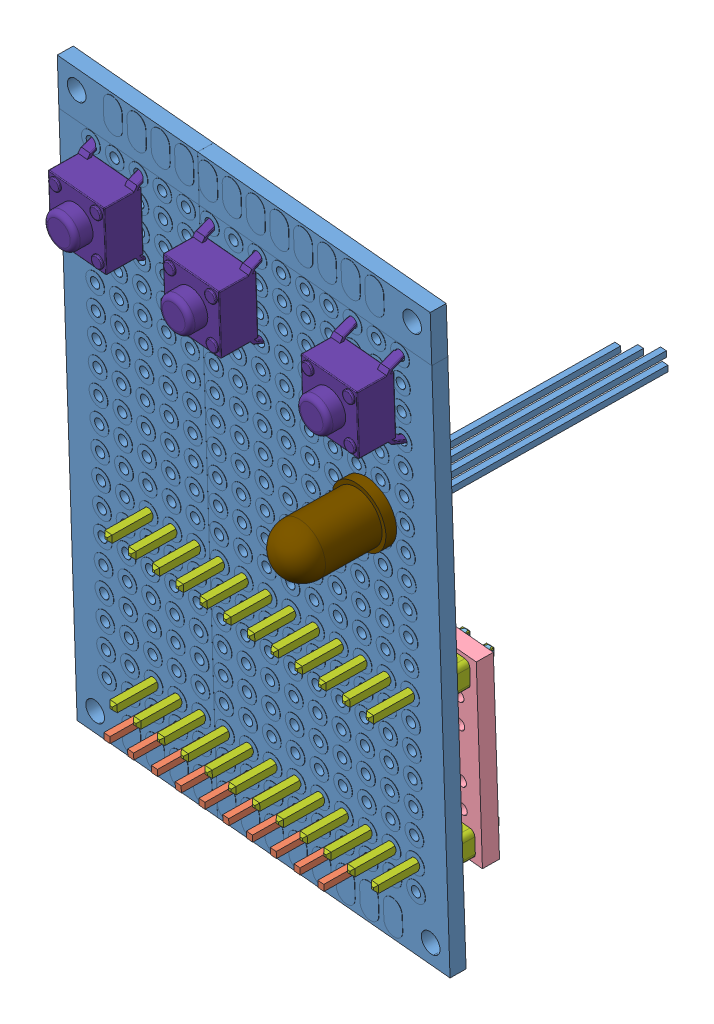
SolidWorks assembly Board avec pièce, configuration Défaut. Lengths in mm.
Overall size (41.2 60.87 36.28).
30 component instances, 20 part files, 9 mates.
Components (placement in the parent):
- board 6x4-2: board 6x4 [Défaut] at (-21.2391 31.2472 3.4753) x (-0.022456 -0.998207 -0.055493) z (-0.066606 -0.05389 0.996323) size (59.85 39.85 1.55)
- User Library-ARDUINO_MINI_V1-2: User Library-ARDUINO_MINI_V1 [Default] at (-31.669 21.8561 -0.738) x (0.997527 -0.02607 0.065277) z (0.022456 0.998207 0.055493) size (34 18.6 18.6)
  - User Library-ARDUINO_MINI_V1_ARDUINO_MINI_1-1: User Library-ARDUINO_MINI_V1_ARDUINO_MINI_1 [Default] at (18.8931 -34 -14.1188) x (0 0 1) z (0 1 0) size (18.6 34 18.6)
    - User Library-ARDUINO_MINI_V1_button_reset_1-1: User Library-ARDUINO_MINI_V1_button_reset_1 [Default] at (7.2736 10.2071 35.6) x (1 0 0) z (0 -1 0) size (5.2 2.15 3)
      - User Library-ARDUINO_MINI_V1_reset core-1: User Library-ARDUINO_MINI_V1_reset core [Default] at origin size (5.2 2.15 2.8)
      - User Library-ARDUINO_MINI_V1_reset shell-1: User Library-ARDUINO_MINI_V1_reset shell [Default] at (0 1.65 0) x (0 0 1) z (-1 0 0) size (3 1.65 4)
    - User Library-ARDUINO_MINI_V1_Mini_board_1-1: User Library-ARDUINO_MINI_V1_Mini_board_1 [Default] at (4.8188 -1.8931 34) size (18.6 34 1.6)
    - User Library-ARDUINO_MINI_V1_mini-solder-1-1: User Library-ARDUINO_MINI_V1_mini-solder-1 [Default] at (12.4388 -22.4531 33.999) x (0 1 0) z (1 0 0) size (29.74 1.5 17.04)
    - User Library-ARDUINO_MINI_V1_mini-solder-2-1: User Library-ARDUINO_MINI_V1_mini-solder-2 [Default] at (-9.1512 -2.1531 35.601) x (1 0 0) z (0 1 0) size (14.5 1.5 1.8)
    - User Library-ARDUINO_MINI_V1_12pin_header-1: User Library-ARDUINO_MINI_V1_12pin_header [Default] at (12.4388 -14.8326 34) x (1 0 0) z (0 1 0) size (2.54 11.75 30.48)
    - User Library-ARDUINO_MINI_V1_12pin_header-2: User Library-ARDUINO_MINI_V1_12pin_header [Default] at (-2.8012 -14.8326 34) x (1 0 0) z (0 1 0) size (2.54 11.75 30.48)
    - User Library-ARDUINO_MINI_V1_6pin_header-1: User Library-ARDUINO_MINI_V1_6pin_header [Default] at (11.1688 -17.3935 35.6) x (0 -1 0) z (-1 0 0) size (2.54 11.75 15.24)
    - User Library-ARDUINO_MINI_V1_atmega328-1: User Library-ARDUINO_MINI_V1_atmega328 [Default] at (5.1227 0.4003 35.7) x (0.66262 -0.748956 0) z (-0.748956 -0.66262 0) size (10 1.1 10)
    - User Library-ARDUINO_MINI_V1_16mhz crystal - measured-1: User Library-ARDUINO_MINI_V1_16mhz crystal - measured [Default] at (8.0304 7.0786 35.6) x (1 0 0) z (0 -1 0) size (3.4 0.8 2)
    - User Library-ARDUINO_MINI_V1_cap106C-1: User Library-ARDUINO_MINI_V1_cap106C [Default] at (8.8938 -11.0448 35.6) x (1 0 0) z (0 -1 0) size (1.7 1.81 4)
    - User Library-ARDUINO_MINI_V1_cap106C-2: User Library-ARDUINO_MINI_V1_cap106C [Default] at (0.7785 -11.0448 35.6) x (1 0 0) z (0 -1 0) size (1.7 1.81 4)
    - User Library-ARDUINO_MINI_V1_led-1: User Library-ARDUINO_MINI_V1_led [Default] at (5.5955 -6.4562 35.6) x (1 0 0) z (0 -1 0) size (4 0.86 1.35)
    - User Library-ARDUINO_MINI_V1_led-2: User Library-ARDUINO_MINI_V1_led [Default] at (1.4134 10.422 35.6) x (1 0 0) z (0 -1 0) size (4 0.86 1.35)
    - User Library-ARDUINO_MINI_V1_NANO DIODE-1: User Library-ARDUINO_MINI_V1_NANO DIODE [Default] at (5.2494 -12.0297 35.6) x (1 0 0) z (0 -1 0) size (4.92 1.36 1.7)
    - User Library-ARDUINO_MINI_V1_102 RESISTOR PACK-1: User Library-ARDUINO_MINI_V1_102 RESISTOR PACK [Default] at (6.0229 -8.9591 35.6) x (0 -1 0) z (-1 0 0) size (3.2 0.46 3)
    - User Library-ARDUINO_MINI_V1_smt_resistor222-1: User Library-ARDUINO_MINI_V1_smt_resistor222 [Default] at (1.4153 6.538 35.6) x (0 1 0) z (1 0 0) size (1.7 0.6 3.8)
    - User Library-ARDUINO_MINI_V1_smt_resistor222-2: User Library-ARDUINO_MINI_V1_smt_resistor222 [Default] at (1.422 8.5266 35.6) x (0 1 0) z (1 0 0) size (1.7 0.6 3.8)
    - User Library-ARDUINO_MINI_V1_603 resistor-1: User Library-ARDUINO_MINI_V1_603 resistor [Default] at (4.8327 6.8612 35.6) x (1 0 0) z (0 -1 0) size (2.36 0.61 1.03)
- button-1: button [Default] at (-32.9172 43.6846 5.0582) x (0.997527 -0.02607 0.065277) z (-0.022456 -0.998207 -0.055493) size (6 8.8 8.45)
- button-2: button [Default] at (-20.3321 43.3429 6.2097) x (0.997527 -0.02607 0.065277) z (-0.022456 -0.998207 -0.055493) size (6 8.8 8.45)
- button-3: button [Default] at (-5.2432 42.9118 7.5621) x (0.997527 -0.02607 0.065277) z (-0.022456 -0.998207 -0.055493) size (6 8.8 8.45)
- Led RGB 5mm-1: Led RGB 5mm [Valor predeterminado] at (-3.2623 33.8035 1.3025) x (0.997523 -0.026224 0.065268) z (-0.02261 -0.998202 -0.055503) size (5.6 35.8 5.8)
  - Lente^Led RGB 5mm-1: Lente^Led RGB 5mm [Valor predeterminado] at origin size (5.6 8.8 5.8) (virtual)
  - Terminais^Led RGB 5mm-1: Terminais^Led RGB 5mm [Valor predeterminado] at origin size (4.82 31.92 1.55) (virtual)
- male header 90 1x10-2: male header 90 1x10 [50] at (-6.4772 2.7553 0.3717) x (-0.997527 0.02607 -0.065277) z (0.022456 0.998207 0.055493) size (25.4 10.22 5.84)
Mates (geometry in assembly coordinates):
- Verrouiller1: lock: unknown of board 6x4-2; unknown of ?
- Verrouiller2: lock: unknown of board 6x4-2; unknown of button-1
- Verrouiller3: lock: unknown of board 6x4-2; unknown of button-2
- Verrouiller4: lock: unknown of board 6x4-2; unknown of button-3
- Verrouiller6: lock: unknown of board 6x4-2; unknown of ?
- Coïncidente1: coincident anti-aligned: plane of board 6x4-2 through (-20.5481 31.8062 -6.8603) normal (-0.066606 -0.05389 0.996323); plane of ? through (-12.6329 2.0613 -7.94) normal (0.066606 0.05389 -0.996323)
- Coïncidente3: coincident: plane of board 6x4-2 through (-21.2391 31.2472 3.4753) normal (0.066606 0.05389 -0.996323); plane of male header 90 1x10-2 through (-6.6464 2.6184 2.9024) normal (-0.066606 -0.05389 0.996323)
- Parallèle1: parallel: plane of board 6x4-2 through (2.9131 -4.3418 3.165) normal (-0.022456 -0.998207 -0.055493); plane of male header 90 1x10-2 through (-26.6126 0.9564 1.4777) normal (-0.022456 -0.998207 -0.055493)
- Verrouiller7: lock: unknown of board 6x4-2; unknown of male header 90 1x10-2
